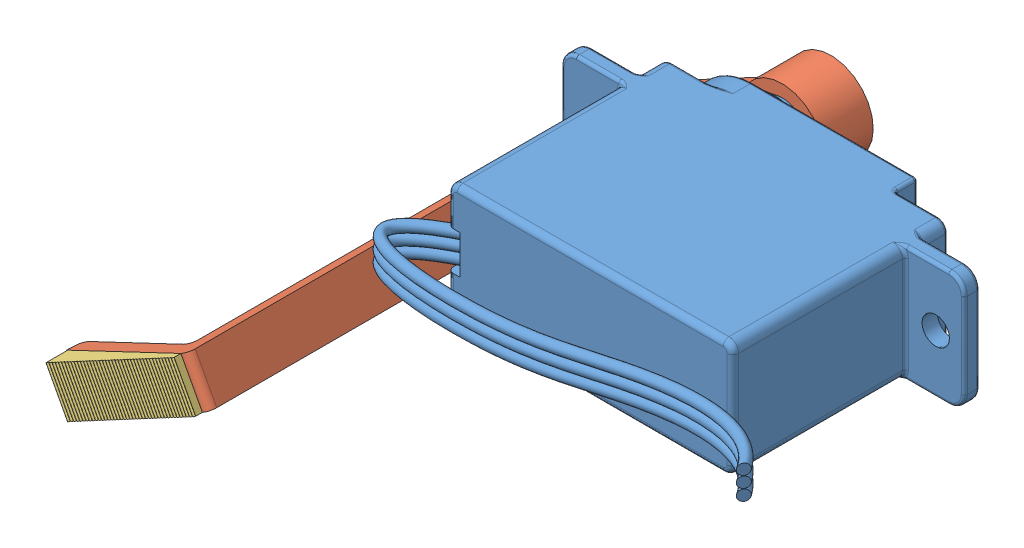
SolidWorks assembly Motor_Leg_Assembly, configuration Default. Lengths in mm.
Overall size (39.67 16.75 32.59).
4 component instances, 4 part files, 11 mates.
Components (placement in the parent):
- Hitec HS-35HD Ultra Nano Servo_NonTransparentCAD-1: Hitec HS-35HD Ultra Nano Servo_NonTransparentCAD [Default] x (1 0 0) z (0 0 -1) size (27.16 7.75 23.55)
- Leg-1: Leg [Default] at (4.4196 -3.81 -20.7518) x (-0.471147 0.882054 0) z (0.882054 0.471147 0) size (5.59 30.95 24.89)
- Grip-1: Grip [Default] at (-6.6061 -9.6993 10.2032) x (-0.882054 -0.471147 0) z (0.471147 -0.882054 0) size (9.5 1.45 3)
- nylon_screw_M1x4x3.5-1: nylon_screw_M1x4x3.5 [M1.6 x 4 - Z --4N] at (4.4196 -3.81 -21.9248) x (0 0 1) z (-1 0 0) size (5.27 3.2 3.2)
Mates (geometry in assembly coordinates):
- Coincident14: coincident anti-aligned: plane of Hitec HS-35HD Ultra Nano Servo_NonTransparentCAD-1 through (4.4196 -3.81 -19.6596) normal (0 0 -1); plane of Leg-1 through (4.4196 -3.81 -19.6596) normal (0 0 1)
- Concentric13: concentric aligned: cylinder of Hitec HS-35HD Ultra Nano Servo_NonTransparentCAD-1 through (4.4196 -3.81 -17.1196) axis (0 0 -1) radius 0.508; cylinder of Leg-1 through (4.4196 -3.81 -17.5387) axis (0 0 -1) radius 1.8415
- Distance1: distance = 0.5 mm aligned: plane of Leg-1 through (-6.8718 -8.1407 9.2482) normal (0.882054 0.471147 0); plane of Grip-1 through (-5.8994 -11.0224 10.7032) normal (0.882054 0.471147 0)
- Coincident23: coincident aligned: plane of Grip-1 through (-5.8994 -11.0224 10.2032) normal (0.471147 -0.882054 0); plane of Leg-1 through (-0.6988 -8.2445 -19.6596) normal (0.471147 -0.882054 0)
- Coincident24: coincident anti-aligned: plane of Leg-1 through (-9.5154 -24.6274 9.2432) normal (-0.087768 -0.046881 0.995037); plane of Grip-1 through (-5.8994 -11.0224 10.2032) normal (0.087768 0.046881 -0.995037)
- Coincident25: coincident anti-aligned: plane of Hitec HS-35HD Ultra Nano Servo_NonTransparentCAD-1 through (0 0 0) normal (0 -1 0)
- Coincident26: coincident aligned: plane of Hitec HS-35HD Ultra Nano Servo_NonTransparentCAD-1 through (0 0 0) normal (1 0 0)
- Coincident27: coincident anti-aligned: plane of Hitec HS-35HD Ultra Nano Servo_NonTransparentCAD-1 through (0 0 0) normal (0 0 -1)
- Concentric14: concentric aligned: cylinder of Hitec HS-35HD Ultra Nano Servo_NonTransparentCAD-1 through (4.4196 -3.81 -17.1196) axis (0 0 -1) radius 0.508; cylinder of nylon_screw_M1x4x3.5-1 through (4.4196 -3.81 -47.3248) axis (0 0 -1) radius 0.8
- Coincident28: coincident anti-aligned: plane of Leg-1 through (4.4196 -3.81 -20.6248) normal (0 0 -1); plane of nylon_screw_M1x4x3.5-1 through (4.4196 -3.01 -20.6248) normal (0 0 1)
- Parallel1: parallel aligned: plane of Hitec HS-35HD Ultra Nano Servo_NonTransparentCAD-1 through (0 -7.62 -14.1224) normal (0 -1 0); plane of nylon_screw_M1x4x3.5-1 through (3.6196 -3.57 -21.9248) normal (0 -1 0)
